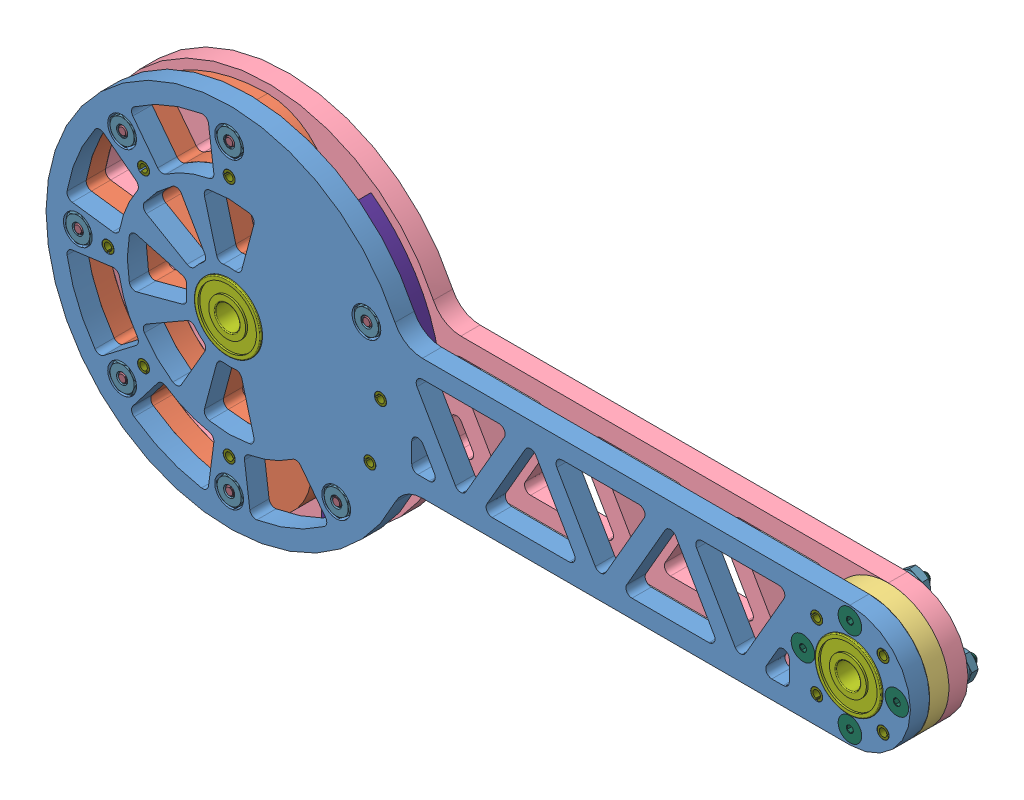
SolidWorks assembly A_3_000, configuration Default. Lengths in mm.
Overall size (287.08 121 26.4).
52 component instances, 17 part files, 61 mates.
Components (placement in the parent):
- A_3_001-1: A_3_001 [Default] at (56.5955 187.4123 219.4124) size (285.5 121 6.35)
- A_3_002-1: A_3_002 [Default] at (56.5955 187.4123 213.0624) size (78.5 115 6.35)
- A_3_004-1: A_3_004 [Default] at (261.5955 187.4123 213.0624) size (40 40 6.35)
- A_3_005-1: A_3_005 [Default] at (56.5955 187.4123 206.7124) size (285.5 121 6.35)
- A_3_006-1: A_3_006 [Default] at (74.0955 198.0623 219.4124) x (1 0 0) z (0 1 0) size (27 6.35 6.35)
- A_3_007-3: A_3_007 [Default] at (97.0955 183.3405 219.4124) x (-1 0 0) z (0 0 1) size (27.5 6.35 12.7)
- 110300107560_B608ZZ-5: 110300107560_B608ZZ [Default] at (56.5955 187.4123 219.4124) x (0 0 1) z (-1 0 0) size (7 22 22)
- 110300107560_B608ZZ-6: 110300107560_B608ZZ [Default] at (56.5955 187.4123 206.0624) x (0 0 1) z (-0.397708 -0.917512 0) size (7 22 22)
- 110300107560_B608ZZ-3: 110300107560_B608ZZ [Default] at (261.5955 187.4123 219.4124) x (0 0 1) z (-1 0 0) size (7 22 22)
- 110300107560_B608ZZ-4: 110300107560_B608ZZ [Default] at (261.5955 187.4123 206.0624) x (0 0 1) z (0.840404 -0.541961 0) size (7 22 22)
- 110300250540_LBNR6-1: 110300250540_LBNR6 [Default] at (261.5955 187.4123 203.5624) x (0 0 1) z (-0.980449 -0.196773 0) size (5 11.5 10)
- 94065K340-1: 94065K340 [94065K34] at (56.5955 187.4123 206.0624) x (0.676872 -0.7361 0) z (0.7361 0.676872 0) size (15.8 0.55 15.8)
- 98055A114-5: 98055A114 [Default] at (56.5955 187.4123 205.0124) size (14 14 0.5)
- 98055A114-6: 98055A114 [Default] at (56.5955 187.4123 204.5124) size (14 14 0.5)
- 98055A114-7: 98055A114 [Default] at (56.5955 187.4123 203.5124) x (0.998383 0.056846 0) z (0 0 1) size (14 14 0.5)
- 98892A200-1: 98892A200 [98892A200] at (87.5955 177.989 216.2374) x (0.866025 0 0.5) z (0 1 0) size (6.2 6.2 3.77)
- 92196A168-1: 92196A168 [92196A168] at (87.5955 159.9623 216.2374) x (1 0 0) z (0 -1 0) size (5.74 5.74 48.6)
- 92210A151-1: 92210A151 [92210A151] at (56.5955 237.4123 206.7124) x (-1 0 0) z (0 0 -1) size (7.8 7.8 19.48)
- 95170A355-1: 95170A355 [95170A355] at (56.5955 237.4123 222.1905) x (-0.923728 -0.383049 0) z (-0.383049 0.923728 0) size (8.33 3.94 9.17)
- 92210A151-7: 92210A151 [92210A151] at (101.9109 208.5432 206.7124) x (-1 0 0) z (0 0 -1) size (7.8 7.8 19.48)
- 95170A355-7: 95170A355 [95170A355] at (101.9109 208.5432 222.1905) x (-0.544843 0.838538 0) z (0.838538 0.544843 0) size (8.33 3.94 9.17)
- 92210A153-1: 92210A153 [92210A153] at (261.5955 202.9123 225.7624) size (7.8 7.8 25.87)
- 95170A355-8: 95170A355 [95170A355] at (261.5955 202.9123 206.7124) x (-0.597523 0.801852 0) z (-0.801852 -0.597523 0) size (8.33 3.94 9.17)
- 92373A215-1: 92373A215 [92373A215] at (56.5955 227.4123 216.2374) size (4.08 4.11 19.05)
- 92373A215-6: 92373A215 [92373A215] at (103.0629 168.952 216.2374) size (4.08 4.11 19.05)
- 92373A215-12: 92373A215 [92373A215] at (106.5743 188.8666 216.2374) size (4.08 4.11 19.05)
- 92373A215-8: 92373A215 [92373A215] at (250.6353 198.3725 216.2374) size (4.08 4.11 19.05)
- 98055A114-8: 98055A114 [Default] at (56.5955 187.4123 204.0124) x (0.999544 -0.030193 0) z (0 0 1) size (14 14 0.5)
- 95170A355-2: 95170A355 [95170A355] at (91.9508 152.057 222.1905) x (0.382318 0.924031 0) z (0.924031 -0.382318 0) size (8.33 3.94 9.17)
- 95170A355-3: 95170A355 [95170A355] at (56.5955 137.4123 222.1905) x (0.923728 0.383049 0) z (0.383049 -0.923728 0) size (8.33 3.94 9.17)
- 95170A355-4: 95170A355 [95170A355] at (21.2401 152.057 222.1905) x (0.924031 -0.382318 0) z (-0.382318 -0.924031 0) size (8.33 3.94 9.17)
- 95170A355-5: 95170A355 [95170A355] at (6.5955 187.4123 222.1905) x (0.383049 -0.923728 0) z (-0.923728 -0.383049 0) size (8.33 3.94 9.17)
- 95170A355-6: 95170A355 [95170A355] at (21.2401 222.7677 222.1905) x (-0.382318 -0.924031 0) z (-0.924031 0.382318 0) size (8.33 3.94 9.17)
- 92210A151-2: 92210A151 [92210A151] at (91.9508 152.057 206.7124) x (0.707107 0.707107 0) z (0 0 -1) size (7.8 7.8 19.48)
- 92210A151-3: 92210A151 [92210A151] at (56.5955 137.4123 206.7124) x (1 0 0) z (0 0 -1) size (7.8 7.8 19.48)
- 92210A151-4: 92210A151 [92210A151] at (21.2401 152.057 206.7124) x (0.707107 -0.707107 0) z (0 0 -1) size (7.8 7.8 19.48)
- 92210A151-5: 92210A151 [92210A151] at (6.5955 187.4123 206.7124) x (0 -1 0) z (0 0 -1) size (7.8 7.8 19.48)
- 92210A151-6: 92210A151 [92210A151] at (21.2401 222.7677 206.7124) x (-0.707107 -0.707107 0) z (0 0 -1) size (7.8 7.8 19.48)
- 95170A355-9: 95170A355 [95170A355] at (277.0955 187.4123 206.7124) x (0.801852 0.597523 0) z (-0.597523 0.801852 0) size (8.33 3.94 9.17)
- 95170A355-10: 95170A355 [95170A355] at (261.5955 171.9123 206.7124) x (0.597523 -0.801852 0) z (0.801852 0.597523 0) size (8.33 3.94 9.17)
- 95170A355-11: 95170A355 [95170A355] at (246.0955 187.4123 206.7124) x (-0.801852 -0.597523 0) z (0.597523 -0.801852 0) size (8.33 3.94 9.17)
- 92210A153-2: 92210A153 [92210A153] at (277.0955 187.4123 225.7624) x (0 -1 0) z (0 0 1) size (7.8 7.8 25.87)
- 92210A153-3: 92210A153 [92210A153] at (261.5955 171.9123 225.7624) x (-1 0 0) z (0 0 1) size (7.8 7.8 25.87)
- 92210A153-4: 92210A153 [92210A153] at (246.0955 187.4123 225.7624) x (0 1 0) z (0 0 1) size (7.8 7.8 25.87)
- 92373A215-2: 92373A215 [92373A215] at (56.5955 147.4123 216.2374) x (-1 0 0) z (0 0 1) size (4.08 4.11 19.05)
- 92373A215-3: 92373A215 [92373A215] at (28.3112 159.1281 216.2374) x (-0.707107 0.707107 0) z (0 0 1) size (4.08 4.11 19.05)
- 92373A215-4: 92373A215 [92373A215] at (16.5955 187.4123 216.2374) x (0 1 0) z (0 0 1) size (4.08 4.11 19.05)
- 92373A215-5: 92373A215 [92373A215] at (28.3112 215.6966 216.2374) x (0.707107 0.707107 0) z (0 0 1) size (4.08 4.11 19.05)
- 92373A215-9: 92373A215 [92373A215] at (272.5556 198.3725 216.2374) x (0 -1 0) z (0 0 1) size (4.08 4.11 19.05)
- 92373A215-10: 92373A215 [92373A215] at (272.5556 176.4522 216.2374) x (-1 0 0) z (0 0 1) size (4.08 4.11 19.05)
- 92373A215-11: 92373A215 [92373A215] at (250.6353 176.4522 216.2374) x (0 1 0) z (0 0 1) size (4.08 4.11 19.05)
- A_3_003-1: A_3_003 [Default] at (56.5955 187.4123 213.0624) size (33.33 98.41 6.35)
Mates (geometry in assembly coordinates):
- Concentric1: concentric aligned: cylinder of A_3_001-1 through (56.5955 187.4123 225.7624) axis (0 0 -1) radius 11; cylinder of A_3_002-1 through (56.5955 187.4123 219.4124) axis (0 0 -1) radius 8
- Concentric2: concentric aligned: cylinder of A_3_001-1 through (56.5955 237.4123 225.7624) axis (0 0 -1) radius 1.8986; cylinder of A_3_002-1 through (56.5955 237.4123 219.4124) axis (0 0 -1) radius 1.8986
- Coincident1: coincident anti-aligned: plane of A_3_001-1 through (56.5955 187.4123 219.4124) normal (0 0 -1); plane of A_3_002-1 through (56.5955 187.4123 219.4124) normal (0 0 1)
- Concentric3: concentric aligned: cylinder of A_3_001-1 through (56.5955 187.4123 225.7624) axis (0 0 -1) radius 11; cylinder of A_3_005-1 through (56.5955 187.4123 213.0624) axis (0 0 -1) radius 11
- Concentric4: concentric aligned: cylinder of A_3_001-1 through (56.5955 237.4123 225.7624) axis (0 0 -1) radius 1.8986; cylinder of A_3_005-1 through (56.5955 237.4123 213.0624) axis (0 0 -1) radius 1.8986
- Coincident2: coincident anti-aligned: plane of A_3_002-1 through (56.5955 187.4123 213.0624) normal (0 0 -1); plane of A_3_005-1 through (56.5955 187.4123 213.0624) normal (0 0 1)
- Concentric5: concentric aligned: cylinder of A_3_001-1 through (261.5955 187.4123 225.7624) axis (0 0 -1) radius 11; cylinder of A_3_004-1 through (261.5955 187.4123 219.4124) axis (0 0 -1) radius 8
- Concentric6: concentric aligned: cylinder of A_3_001-1 through (261.5955 202.9123 225.7624) axis (0 0 -1) radius 1.8986; cylinder of A_3_004-1 through (261.5955 202.9123 219.4124) axis (0 0 -1) radius 1.8986
- Coincident3: coincident anti-aligned: plane of A_3_001-1 through (56.5955 187.4123 219.4124) normal (0 0 -1); plane of A_3_004-1 through (261.5955 187.4123 219.4124) normal (0 0 1)
- Concentric7: concentric anti-aligned: cylinder of A_3_001-1 through (56.5955 187.4123 225.7624) axis (0 0 -1) radius 11; cylinder of 110300107560_B608ZZ-5 through (56.5955 187.4123 219.4096) axis (0 0 1) radius 4
- Coincident4: coincident aligned: plane of A_3_001-1 through (56.5955 187.4123 219.4124) normal (0 0 -1); plane of 110300107560_B608ZZ-5 through (56.5955 198.1123 219.4124) normal (0 0 -1)
- Concentric8: concentric anti-aligned: cylinder of A_3_005-1 through (56.5955 187.4123 213.0624) axis (0 0 -1) radius 11; cylinder of 110300107560_B608ZZ-6 through (56.5955 187.4123 206.0596) axis (0 0 1) radius 4
- Coincident5: coincident aligned: plane of A_3_005-1 through (56.5955 187.4123 213.0624) normal (0 0 1); plane of 110300107560_B608ZZ-6 through (47.7415 191.2502 213.0624) normal (0 0 1)
- Concentric9: concentric anti-aligned: cylinder of A_3_001-1 through (261.5955 187.4123 225.7624) axis (0 0 -1) radius 11; cylinder of 110300107560_B608ZZ-3 through (261.5955 187.4123 219.4096) axis (0 0 1) radius 4
- Coincident6: coincident aligned: plane of A_3_001-1 through (56.5955 187.4123 219.4124) normal (0 0 -1); plane of 110300107560_B608ZZ-3 through (261.5955 198.1123 219.4124) normal (0 0 -1)
- Concentric10: concentric anti-aligned: cylinder of A_3_005-1 through (261.5955 187.4123 213.0624) axis (0 0 -1) radius 11; cylinder of 110300107560_B608ZZ-4 through (261.5955 187.4123 206.0596) axis (0 0 1) radius 4
- Coincident7: coincident aligned: plane of A_3_005-1 through (56.5955 187.4123 213.0624) normal (0 0 1); plane of 110300107560_B608ZZ-4 through (256.3656 179.3024 213.0624) normal (0 0 1)
- Concentric11: concentric aligned: cylinder of 110300107560_B608ZZ-6 through (56.5955 187.4123 206.0596) axis (0 0 1) radius 4; cone of 94065K340-1 through (56.5955 187.4123 205.5124) axis (0 0 1)
- Coincident8: coincident anti-aligned: plane of 110300107560_B608ZZ-6 through (50.9987 189.8383 206.0624) normal (0 0 -1); circle of 94065K340-1
- Concentric13: concentric anti-aligned: cylinder of 110300107560_B608ZZ-6 through (56.5955 187.4123 206.0596) axis (0 0 1) radius 4; cylinder of 98055A114-5 through (56.5955 187.4123 205.5124) axis (0 0 -1) radius 4
- Coincident10: coincident aligned: circle of 94065K340-1; plane of 98055A114-5 through (56.5955 187.4123 205.5124) normal (0 0 1)
- Concentric14: concentric anti-aligned: cylinder of 110300107560_B608ZZ-6 through (56.5955 187.4123 206.0596) axis (0 0 1) radius 4; cylinder of 98055A114-6 through (56.5955 187.4123 205.0124) axis (0 0 -1) radius 4
- Coincident11: coincident anti-aligned: plane of 98055A114-5 through (56.5955 187.4123 205.0124) normal (0 0 -1); plane of 98055A114-6 through (56.5955 187.4123 205.0124) normal (0 0 1)
- Concentric15: concentric anti-aligned: cylinder of 110300107560_B608ZZ-6 through (56.5955 187.4123 206.0596) axis (0 0 1) radius 4; cylinder of 98055A114-7 through (56.5955 187.4123 204.0124) axis (0 0 -1) radius 4
- Coincident20: coincident anti-aligned: plane of A_3_001-1 through (56.5955 187.4123 219.4124) normal (0 0 -1); plane of A_3_006-1 through (74.0955 204.4123 219.4124) normal (0 0 1)
- Concentric32: concentric anti-aligned: cylinder of A_3_006-1 through (87.5955 204.4123 216.2374) axis (0 -1 0) radius 2.16; circle of 98892A200-1
- Concentric33: concentric aligned: cylinder of A_3_006-1 through (87.5955 204.4123 216.2374) axis (0 -1 0) radius 2.16; circle of 92196A168-1
- Coincident39: coincident anti-aligned: plane of A_3_006-1 through (74.0955 204.4123 213.0624) normal (0 1 0); plane of 92196A168-1 through (87.5955 204.4123 216.2374) normal (0 -1 0)
- Parallel1: parallel aligned: plane of A_3_001-1 through (56.5955 187.4123 219.4124) normal (0 0 -1); plane of 98892A200-1 through (88.9703 179.775 213.8561) normal (0 0 -1)
- Coincident45: coincident anti-aligned: plane of A_3_001-1 through (56.5955 187.4123 219.4124) normal (0 0 -1); plane of A_3_007-3 through (97.0955 176.9905 219.4124) normal (0 0 1)
- Concentric46: concentric anti-aligned: cylinder of A_3_006-1 through (79.183 204.4123 216.2374) axis (0 -1 0) radius 1.5875; cylinder of A_3_007-3 through (79.183 176.9905 216.2374) axis (0 1 0) radius 1.5875
- Coincident46: coincident anti-aligned: plane of 98892A200-1 through (87.5955 176.9905 216.2374) normal (0 1 0); plane of A_3_007-3 through (97.0955 176.9905 219.4124) normal (0 -1 0)
- Concentric59: concentric anti-aligned: cylinder of 110300107560_B608ZZ-4 through (261.5955 187.4123 206.0596) axis (0 0 1) radius 4; circle of 110300250540_LBNR6-1
- Coincident56: coincident anti-aligned: plane of 110300107560_B608ZZ-4 through (258.2895 182.2859 206.0624) normal (0 0 -1); plane of 110300250540_LBNR6-1 through (261.5955 187.4123 206.0624) normal (0 0 1)
- Concentric60: concentric anti-aligned: cylinder of A_3_005-1 through (56.5955 237.4123 213.0624) axis (0 0 -1) radius 1.8986; circle of 92210A151-1
- Coincident57: coincident aligned: plane of A_3_005-1 through (56.5955 187.4123 206.7124) normal (0 0 -1); plane of 92210A151-1 through (56.5955 235.6597 206.7124) normal (0 0 -1)
- Concentric62: concentric aligned: cylinder of A_3_001-1 through (56.5955 237.4123 222.1905) axis (0 0 1) radius 4.7625; circle of 95170A355-1
- Coincident58: coincident anti-aligned: plane of A_3_001-1 through (56.5955 237.4123 222.1905) normal (0 0 1); plane of 95170A355-1 through (58.3509 233.1791 222.1905) normal (0 0 -1)
- Concentric63: concentric anti-aligned: cylinder of A_3_005-1 through (101.9109 208.5432 213.0624) axis (0 0 -1) radius 1.8986; circle of 92210A151-7
- Coincident59: coincident aligned: plane of A_3_005-1 through (56.5955 187.4123 206.7124) normal (0 0 -1); plane of 92210A151-7 through (101.9109 206.7906 206.7124) normal (0 0 -1)
- Concentric64: concentric aligned: cylinder of A_3_001-1 through (101.9109 208.5432 222.1905) axis (0 0 1) radius 4.7625; circle of 95170A355-7
- Coincident60: coincident anti-aligned: plane of A_3_001-1 through (101.9109 208.5432 222.1905) normal (0 0 1); plane of 95170A355-7 through (98.0681 206.0464 222.1905) normal (0 0 -1)
- Concentric65: concentric aligned: cylinder of A_3_001-1 through (261.5955 202.9123 225.7624) axis (0 0 -1) radius 1.8986; circle of 92210A153-1
- Coincident61: coincident aligned: plane of A_3_001-1 through (56.5955 187.4123 225.7624) normal (0 0 1); plane of 92210A153-1 through (261.5955 201.1597 225.7624) normal (0 0 1)
- Concentric66: concentric aligned: cylinder of A_3_005-1 through (261.5955 202.9123 213.0624) axis (0 0 -1) radius 1.8986; circle of 95170A355-8
- Coincident62: coincident anti-aligned: plane of A_3_005-1 through (56.5955 187.4123 206.7124) normal (0 0 -1); plane of 95170A355-8 through (265.2701 205.6506 206.7124) normal (0 0 1)
- Concentric67: concentric aligned: cylinder of A_3_001-1 through (56.5955 227.4123 225.7624) axis (0 0 -1) radius 1.9939; circle of 92373A215-1
- Coincident63: coincident aligned: plane of A_3_001-1 through (56.5955 187.4123 225.7624) normal (0 0 1); plane of 92373A215-1 through (56.5955 227.4123 225.7624) normal (0 0 1)
- Concentric68: concentric aligned: cylinder of A_3_001-1 through (103.0629 168.952 225.7624) axis (0 0 -1) radius 1.9939; circle of 92373A215-6
- Coincident64: coincident aligned: plane of A_3_001-1 through (56.5955 187.4123 225.7624) normal (0 0 1); plane of 92373A215-6 through (103.0629 168.952 225.7624) normal (0 0 1)
- Concentric69: concentric aligned: cylinder of A_3_001-1 through (106.5743 188.8666 225.7624) axis (0 0 -1) radius 1.9939; circle of 92373A215-12
- Coincident65: coincident aligned: plane of A_3_001-1 through (56.5955 187.4123 225.7624) normal (0 0 1); plane of 92373A215-12 through (106.5743 188.8666 225.7624) normal (0 0 1)
- Concentric70: concentric aligned: cylinder of A_3_001-1 through (250.6353 198.3725 225.7624) axis (0 0 -1) radius 1.9939; circle of 92373A215-8
- Coincident66: coincident aligned: plane of A_3_001-1 through (56.5955 187.4123 225.7624) normal (0 0 1); plane of 92373A215-8 through (250.6353 198.3725 225.7624) normal (0 0 1)
- Concentric71: concentric aligned: cylinder of 98055A114-6 through (56.5955 187.4123 205.0124) axis (0 0 -1) radius 4; cylinder of 98055A114-8 through (56.5955 187.4123 204.5124) axis (0 0 -1) radius 4
- Coincident67: coincident anti-aligned: plane of 98055A114-6 through (56.5955 187.4123 204.5124) normal (0 0 -1); plane of 98055A114-8 through (56.5955 187.4123 204.5124) normal (0 0 1)
- Coincident68: coincident anti-aligned: plane of A_3_002-1 through (74.0955 198.0623 219.4124) normal (0 1 0); plane of A_3_006-1 through (74.0955 198.0623 213.0624) normal (0 -1 0)
- Coincident69: coincident anti-aligned: plane of A_3_002-1 through (74.0955 204.4123 219.4124) normal (1 0 0); plane of A_3_006-1 through (74.0955 204.4123 219.4124) normal (-1 0 0)
- Concentric72: concentric: cylinder of A_3_001-1 through (101.9109 208.5432 225.7624) axis (0 0 -1) radius 1.8986; cylinder of A_3_003-1 through (101.9109 208.5432 219.4124) axis (0 0 -1) radius 1.8986
- Concentric73: concentric: cylinder of A_3_001-1 through (91.9508 152.057 225.7624) axis (0 0 -1) radius 1.8986; cylinder of A_3_003-1 through (91.9508 152.057 219.4124) axis (0 0 -1) radius 1.8986
- Coincident70: coincident anti-aligned: plane of A_3_001-1 through (56.5955 187.4123 219.4124) normal (0 0 -1); plane of A_3_003-1 through (56.5955 187.4123 219.4124) normal (0 0 1)
